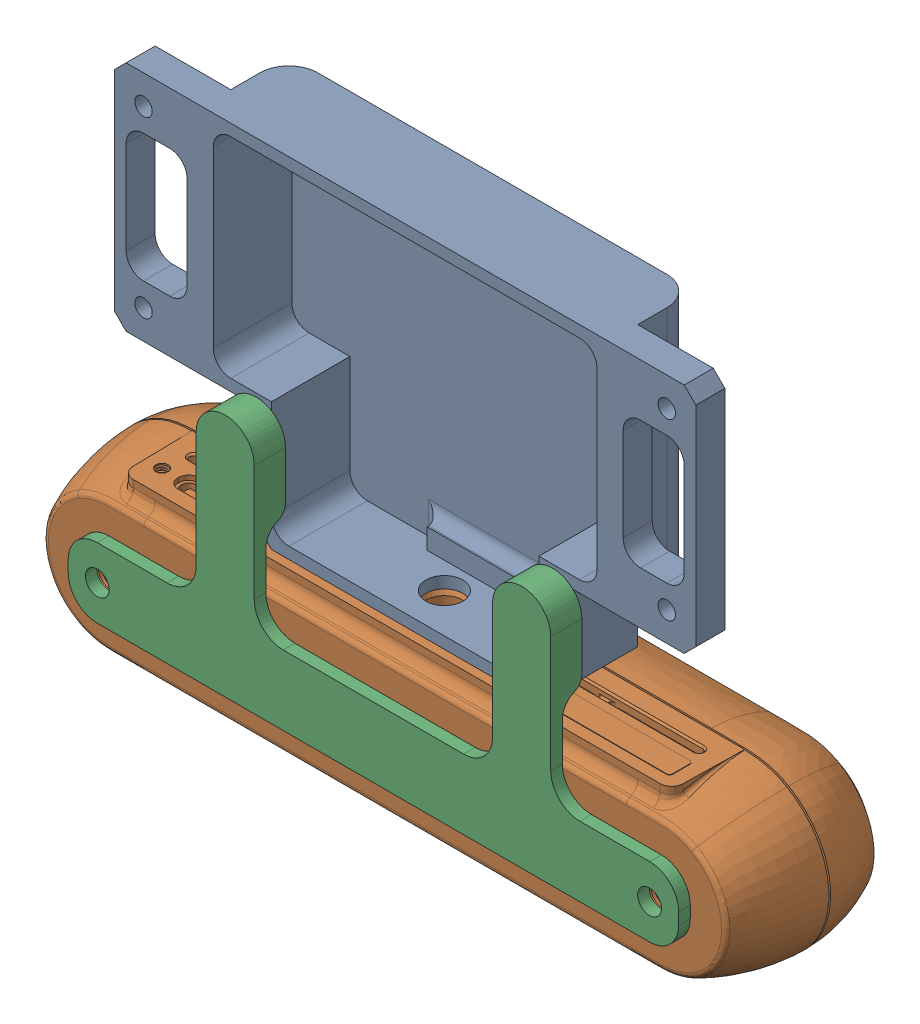
SolidWorks assembly realsense_subassembly, configuration Default. Lengths in mm.
Overall size (124 89 28.55).
3 component instances, 3 part files, 5 mates.
Components (placement in the parent):
- body_structure_front-1: body_structure_front [Standard] at origin size (100 60 15)
- D455f_Solid-1: D455f_Solid [default] at (0 -54.5 -20.045) x (1 0 0) z (0 0 -1) size (124 29.09 26.56)
- realsense_stopper-1: realsense_stopper [Default] at (0 -54.5 5.955) x (-1 0 0) z (0 1 0) size (105 5.35 42)
Mates (geometry in assembly coordinates):
- Coincident1: coincident anti-aligned: plane of body_structure_front-1 through (-25 -40 -2.5) normal (0 -1 0); plane of D455f_Solid-1 through (0 -40 -20.045) normal (0 1 0)
- Concentric1: concentric aligned: circle of D455f_Solid-1; circle of realsense_stopper-1
- Concentric2: concentric aligned: circle of D455f_Solid-1; circle of realsense_stopper-1
- Coincident2: coincident anti-aligned: plane of D455f_Solid-1 through (0 -54.5 5.955) normal (0 0 1); plane of realsense_stopper-1 through (0 -54.5 5.955) normal (0 0 -1)
- Coincident3: coincident anti-aligned: cylinder of body_structure_front-1 through (0 -30 -4.25) axis (0 -1 0) radius 3.175; circle of D455f_Solid-1
